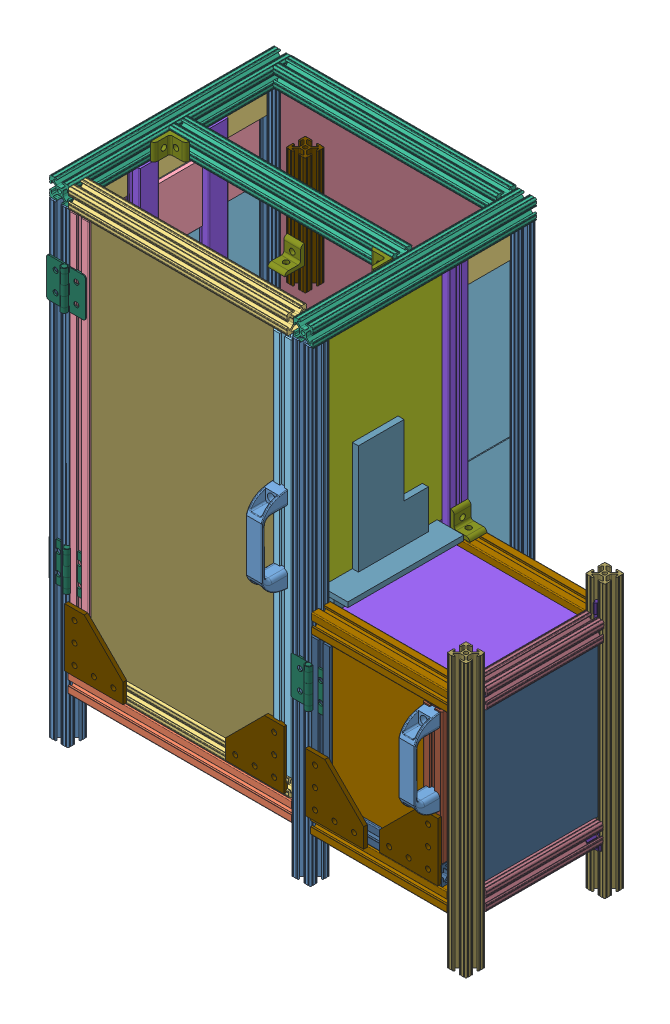
SolidWorks assembly Box_Miniscope_12.15.23, configuration Default. Lengths in mm.
Overall size (547.36 663.01 328.21).
94 component instances, 37 part files, 0 mates.
Components (placement in the parent):
- 24in47065T801_T-Slotted Framing-3: 24in47065T801_T-Slotted Framing [47065T801] at (-148.3949 609.6 -36.7617) x (1 0 0) z (0 -1 0) size (25.4 25.4 609.6)
- 24in47065T801_T-Slotted Framing-4: 24in47065T801_T-Slotted Framing [47065T801] at (168.7277 611.3932 -36.4525) x (1 0 0) z (0 -1 0) size (25.4 25.4 609.6)
- 11_5in6575N217_T-Slotted Framing Rail-4: 11_5in6575N217_T-Slotted Framing Rail [6575N217] at (10.5466 379.0665 -36.3692) x (0 0 -1) z (-1 0 0) size (25.4 25.4 292.1)
- 11_25in47065T846_T-Slotted Framing-3: 11_25in47065T846_T-Slotted Framing [47065T846] at (10.2279 404.6784 -36.3352) x (0 1 0) z (1 0 0) size (25.4 25.4 285.75)
- 11_25in47065T846_T-Slotted Framing-4: 11_25in47065T846_T-Slotted Framing [47065T846] at (7.8735 926.401 -36.5473) x (0 1 0) z (1 0 0) size (25.4 25.4 285.75)
- 19_5in6575N217_T-Slotted Framing Rail-2: 19_5in6575N217_T-Slotted Framing Rail [6575N217] at (-120.6393 666.1262 -36.1499) x (-1 0 0) z (0 1 0) size (25.4 25.4 495.3)
- 19_5in6575N218_T-Slotted Framing Rail-2: 19_5in6575N218_T-Slotted Framing Rail [6575N218] at (144.1698 664.3767 -36.7725) x (0 -1 0) z (0 0 -1) size (495.3 25.4 25.4)
- 24in47065T801_T-Slotted Framing-5: 24in47065T801_T-Slotted Framing [47065T801] at (168.71 609.2978 -305.5515) x (0 0 -1) z (0 1 0) size (25.4 25.4 609.6)
- 24in47065T801_T-Slotted Framing-6: 24in47065T801_T-Slotted Framing [47065T801] at (-148.3772 610.174 -305.8603) x (0 0 1) z (0 -1 0) size (25.4 25.4 609.6)
- 11_5in6575N217_T-Slotted Framing Rail-3: 11_5in6575N217_T-Slotted Framing Rail [6575N217] at (9.9362 357.1562 -305.5314) x (0 -1 0) z (1 0 0) size (25.4 25.4 292.1)
- 11_5in47065T801_T-Slotted Framing rail-5: 11_5in47065T801_T-Slotted Framing rail [47065T801] at (9.5197 928.5713 -305.435) x (0 1 0) z (-1 0 0) size (25.4 25.4 292.1)
- 9_5in6575N217_T-Slotted Framing Rail-1: 9_5in6575N217_T-Slotted Framing Rail [6575N217] at (167.4188 378.7448 -170.818) x (0 -1 0) z (0 0 1) size (25.4 25.4 241.3)
- 20_5in6575N217_T-Slotted Framing Rail-1: 20_5in6575N217_T-Slotted Framing Rail [6575N217] at (169.0181 653.0398 -217.2746) x (0 0 1) z (0 1 0) size (25.4 25.4 520.7)
- 9_5in6575N217_T-Slotted Framing Rail-2: 9_5in6575N217_T-Slotted Framing Rail [6575N217] at (-148.7212 378.985 -171.6941) size (25.4 25.4 241.3)
- 20_5in6575N217_T-Slotted Framing Rail-3: 20_5in6575N217_T-Slotted Framing Rail [6575N217] at (-147.9442 653.0983 -129.9903) x (0 0 -1) z (0 1 0) size (25.4 25.4 520.7)
- 11_5in47065T801_T-Slotted Framing rail-4: 11_5in47065T801_T-Slotted Framing rail [47065T801] at (-148.9741 926.7859 -172.2295) size (25.4 25.4 292.1)
- 11_5in47065T801_T-Slotted Framing rail-3: 11_5in47065T801_T-Slotted Framing rail [47065T801] at (169.5966 925.9079 -171.9377) size (25.4 25.4 292.1)
- 11_5in47065T801_T-Slotted Framing rail-6: 11_5in47065T801_T-Slotted Framing rail [47065T801] at (9.9058 928.9683 -169.0346) x (0 0 -1) z (1 0 0) size (25.4 25.4 292.1)
- 7in_6575N217_T-Slotted Framing Rail-1: 7in_6575N217_T-Slotted Framing Rail [6575N217] at (271.1061 378.8161 -35.8111) x (0 0 -1) z (-1 0 0) size (25.4 25.4 177.8)
- 7in_6575N217_T-Slotted Framing Rail-2: 7in_6575N217_T-Slotted Framing Rail [6575N217] at (271.3604 604.6105 -36.7818) x (0 0 1) z (-1 0 0) size (25.4 25.4 177.8)
- 6_75in6575N217_T-Slotted Framing Rail-1: 6_75in6575N217_T-Slotted Framing Rail [6575N217] at (194.7736 504.9941 -36.2462) x (-1 0 0) z (0 1 0) size (25.4 25.4 171.45)
- 6_75in6575N217_T-Slotted Framing Rail-2: 6_75in6575N217_T-Slotted Framing Rail [6575N217] at (267.6114 404.8421 -35.8111) x (0 0 1) z (-1 0 0) size (25.4 25.4 171.45)
- 6_75__6575N218_T-Slotted Framing Rail-1: 6_75__6575N218_T-Slotted Framing Rail [6575N218] at (340.4492 503.9229 -36.2462) x (0 -1 0) z (0 0 -1) size (171.45 25.4 25.4)
- 7in_6575N217_T-Slotted Framing Rail-4: 7in_6575N217_T-Slotted Framing Rail [6575N217] at (270.952 378.5991 -217.604) x (0 0 -1) z (-1 0 0) size (25.4 25.4 177.8)
- 7in_6575N217_T-Slotted Framing Rail-5: 7in_6575N217_T-Slotted Framing Rail [6575N217] at (270.952 604.0749 -217.5035) x (0 0 -1) z (1 0 0) size (25.4 25.4 177.8)
- 14_47065T801_T-Slotted Framing-1: 14_47065T801_T-Slotted Framing [47065T801] at (371.9906 482.5001 -36.2612) x (1 0 0) z (0 -1 0) size (25.4 25.4 355.6)
- 14_47065T801_T-Slotted Framing-2: 14_47065T801_T-Slotted Framing [47065T801] at (372.2567 481.9645 -217.2846) x (1 0 0) z (0 -1 0) size (25.4 25.4 355.6)
- 6in_47065T846_T-Slotted Framing-1: 6in_47065T846_T-Slotted Framing [47065T846] at (372.26 379.2027 -125.7835) x (0 -1 0) z (0 0 1) size (25.4 25.4 152.4)
- 6in_47065T846_T-Slotted Framing-2: 6in_47065T846_T-Slotted Framing [47065T846] at (372.2095 606.8098 -127.0918) x (0.999962 -0.008727 0) z (0 0 1) size (25.4 25.4 152.4)
- social_door-1: social_door [Default] at (146.7993 714.5703 -100.9995) x (0 0 -1) z (0 -1 0) size (151.57 54.86 424.8)
- 47065T347_T-Slotted Framing-1: 47065T347_T-Slotted Framing [47065T347] at (181.069 533.8996 -25.7652) size (50.8 51.89 8.3)
- 47065T236_Silver Corner Bracket-1: 47065T236_Silver Corner Bracket [47065T236] at (182.3045 618.2386 -216.7553) size (25.4 25.4 22.23)
- 5537T315_T-Slotted Framing-1: 5537T315_T-Slotted Framing [5537T315] at (372.0391 610.1548 -210.8032) x (0 0 -1) z (0 1 0) size (11.3 21 21)
- 5537T315_T-Slotted Framing-2: 5537T315_T-Slotted Framing [5537T315] at (362.8223 607.2352 -35.7039) x (0 0 1) z (-1 0 0) size (11.3 21 21)
- 47065T236_Silver Corner Bracket-2: 47065T236_Silver Corner Bracket [47065T236] at (181.3564 378.3142 -229.9872) x (1 0 0) z (0 1 0) size (25.4 25.4 22.23)
- 5537T315_T-Slotted Framing-3: 5537T315_T-Slotted Framing [5537T315] at (370.3719 377.8618 -38.5067) x (0 0 -1) z (-1 0 0) size (11.3 21 21)
- 5537T315_T-Slotted Framing-4: 5537T315_T-Slotted Framing [5537T315] at (377.537 378.1435 -216.1498) x (0 0 -1) z (-1 0 0) size (11.3 21 21)
- 5537T315_T-Slotted Framing-5: 5537T315_T-Slotted Framing [5537T315] at (169.9879 383.5329 -40.7588) x (0 0 -1) z (0 -1 0) size (11.3 21 21)
- 5537T315_T-Slotted Framing-6: 5537T315_T-Slotted Framing [5537T315] at (168.2275 604.5945 -41.9909) x (0 0 -1) z (1 0 0) size (11.3 21 21)
- 5537T315_T-Slotted Framing-7: 5537T315_T-Slotted Framing [5537T315] at (170.6355 381.8637 -39.2531) x (-1 0 0) z (0 -0.999962 0.008727) size (11.3 21 21)
- 5537T315_T-Slotted Framing-8: 5537T315_T-Slotted Framing [5537T315] at (368.2177 604.5945 -216.2178) size (11.3 21 21)
- 5537T315_T-Slotted Framing-9: 5537T315_T-Slotted Framing [5537T315] at (373.0966 601.9539 -41.1786) x (-1 0 0) z (0 0 -1) size (11.3 21 21)
- 5537T315_T-Slotted Framing-10: 5537T315_T-Slotted Framing [5537T315] at (364.0014 371.2097 -38.5379) x (1 0 0) z (0 0 -1) size (11.3 21 21)
- 5537T315_T-Slotted Framing-11: 5537T315_T-Slotted Framing [5537T315] at (374.683 376.4911 -207.4156) x (-1 0 0) z (0 0 1) size (11.3 21 21)
- 47065T267_T-Slotted Framing-1: 47065T267_T-Slotted Framing [47065T267] at (181.3084 390.387 -19.4749) size (76.2 76.2 4.76)
- 47065T267_T-Slotted Framing-2: 47065T267_T-Slotted Framing [47065T267] at (352.5726 395.6684 -21.1893) x (0 1 0) z (0 0 1) size (76.2 76.2 4.76)
- 47065T595_Red Plastic Pull Handle-1: 47065T595_Red Plastic Pull Handle [47065T595] at (339.9991 485.6035 -26.6998) size (21.11 112.11 36)
- 47065T595_Red Plastic Pull Handle-2: 47065T595_Red Plastic Pull Handle [47065T595] at (140.8802 637.8823 -26.3458) size (21.11 112.11 36)
- 47065T347_T-Slotted Framing-2: 47065T347_T-Slotted Framing [47065T347] at (-135.5102 507.7072 -26.6883) size (50.8 51.89 8.3)
- 47065T347_T-Slotted Framing-3: 47065T347_T-Slotted Framing [47065T347] at (-136.3904 826.3483 -24.2642) size (50.8 51.89 8.3)
- 47065T267_T-Slotted Framing-3: 47065T267_T-Slotted Framing [47065T267] at (-132.3149 397.4288 -18.8727) size (76.2 76.2 4.76)
- 47065T267_T-Slotted Framing-4: 47065T267_T-Slotted Framing [47065T267] at (149.8575 397.4288 -22.9011) x (0 1 0) z (0 0 1) size (76.2 76.2 4.76)
- lever-2: lever [Default] at (-150.1673 475.0434 -228.178) x (0 0 -1) z (0 -1 0) size (77.83 17.27 82.55)
- lever-3: lever [Default] at (-152.8537 475.9236 -46.8874) x (0 0 -1) z (0 -1 0) size (77.83 17.27 82.55)
- 20_5in6575N217_T-Slotted Framing Rail-4: 20_5in6575N217_T-Slotted Framing Rail [6575N217] at (-149.6364 651.4107 -222.2621) x (0 0 -1) z (0 1 0) size (25.4 25.4 520.7)
- pC-1: pC [Default] at (-151.3902 874.9313 -225.4723) x (0 0 -1) z (0 1 0) size (76.2 4.76 38.1)
- pC-2: pC [Default] at (-151.3902 874.022 -134.5396) x (0 0 -1) z (0 1 0) size (76.2 4.76 38.1)
- pC-3: pC [Default] at (-151.3902 874.9313 -43.607) x (0 0 -1) z (0 1 0) size (76.2 4.76 38.1)
- pB-1: pB [Default] at (-154.7481 799.5031 -300.763) x (0 1 0) z (0 0 1) size (76.2 4.76 76.2)
- pB-2: pB [Default] at (-145.65 797.6844 -213.4676) x (0 1 0) z (0 0 1) size (76.2 4.76 76.2)
- pB-3: pB [Default] at (-153.056 798.5937 -121.6256) x (0 1 0) z (0 0 1) size (76.2 4.76 76.2)
- pA-1: pA [Default] at (-154.7481 596.8761 -299.8537) x (0 1 0) z (0 0 1) size (203.2 4.76 76.2)
- small_Panel_houselight-3: small_Panel_houselight [Default] at (-155.5233 594.5358 -224.073) x (0 0 -1) z (0 -1 0) size (81.28 32 41.27)
- small_Panel_houselight-4: small_Panel_houselight [Default] at (-155.8368 593.6265 -41.9384) x (0 0 -1) z (0 -1 0) size (81.28 32 41.27)
- pA-5: pA [Default] at (-147.1666 592.6741 -207.5193) x (0 1 0) z (0 0 1) size (203.2 4.76 76.2)
- pA-6: pA [Default] at (-148.9828 594.1481 -116.7497) x (0 1 0) z (0 0 1) size (203.2 4.76 76.2)
- pA-7: pA [Default] at (-151.3289 390.27 -210.457) x (0 1 0) z (0 0 1) size (203.2 4.76 76.2)
- pB-7: pB [Default] at (-143.1716 475.7828 -300.7902) x (0 1 0) z (0 0 1) size (76.2 4.76 76.2)
- pB-9: pB [Default] at (-151.3289 474.8735 -117.7031) x (0 1 0) z (0 0 1) size (76.2 4.76 76.2)
- pA-8: pA [Default] at (170.6671 470.4797 -302.5816) x (0 1 0) z (0 0 1) size (203.2 4.76 76.2)
- pA-9: pA [Default] at (169.9555 674.1689 -300.763) x (0 1 0) z (0 0 1) size (203.2 4.76 76.2)
- pC-4: pC [Default] at (173.3134 876.7424 -230.0189) x (0 0 -1) z (0 1 0) size (76.2 4.76 38.1)
- pD-1: pD [Default] at (166.9824 621.9972 -213.3606) x (0 1 0) z (0 0 1) size (298.45 4.76 165.1)
- pG-1: pG [Default] at (187.7197 602.9271 -209.473) size (171.45 4.76 165.1)
- pF-1: pF [Default] at (198.2205 411.574 -31.1345) x (0 1 0) z (1 0 0) size (180.97 4.76 136.53)
- pH-1: pH [Default] at (374.4689 391.1371 -208.814) x (0 1 0) z (0 0 1) size (200.03 4.76 165.1)
- pE-1: pE [Default] at (181.2356 391.3683 -219.3294) x (0 1 0) z (1 0 0) size (203.2 4.76 190.5)
- pJ-1: pJ [Default] at (130.9188 414.9153 -26.2757) x (0 1 0) z (-1 0 0) size (501.65 4.76 250.83)
- pI-1: pI [Default] at (-145.0751 370.6353 -313.66) x (0 1 0) z (1 0 0) size (542.92 4.76 304.8)
- pK-1: pK [Default] at (232.8933 383.0615 -43.7679) x (0 0 -1) z (-1 0 0) size (165.1 4.76 50.8)
- pK-2: pK [Default] at (290.9789 383.0615 -45.5831) x (0 0 -1) z (-1 0 0) size (165.1 4.76 50.8)
- pL-1: pL [Default] at (300.0735 378.299 -45.5831) x (0 0 -1) z (1 0 0) size (165.1 4.76 25.4)
- pL-2: pL [Default] at (333.3517 378.299 -44.373) x (0 0 -1) z (1 0 0) size (165.1 4.76 25.4)
- pN-1: pN [Default] at (-134.9574 369.6788 -296.8821) size (50.8 4.76 254)
- pN-2: pN [Default] at (-76.2667 369.6788 -297.4872) size (50.8 4.76 254)
- pN-3: pN [Default] at (-17.576 369.6788 -297.4872) size (50.8 4.76 254)
- pN-4: pN [Default] at (41.1146 369.5616 -300.5125) size (50.8 4.76 254)
- pM-1: pM [Default] at (99.7435 369.8757 -298.0922) size (23.09 4.76 254)
- pM-2: pM [Default] at (130.6015 370.07 -298.6973) size (23.09 4.76 254)
- 6in_47065T801_T-Slotted Framing-1: 6in_47065T801_T-Slotted Framing [47065T801] at (2.1886 890.9714 -196.2041) x (1 0 0) z (0 -1 0) size (25.4 25.4 152.4)
- 47065T236_Silver Corner Bracket-3: 47065T236_Silver Corner Bracket [47065T236] at (3.0893 845.8313 -183.0471) x (-0.008727 0 0.999962) z (-0.999962 0 -0.008727) size (25.4 25.4 22.23)
- 47065T236_Silver Corner Bracket-8: 47065T236_Silver Corner Bracket [47065T236] at (-134.3586 927.2107 -155.9595) x (1 0 0) z (0 -1 0) size (25.4 25.4 22.23)
- 47065T236_Silver Corner Bracket-9: 47065T236_Silver Corner Bracket [47065T236] at (156.0571 927.6019 -156.5646) x (0 0 1) z (0 -1 0) size (25.4 25.4 22.23)
- food_port_R001-1: food_port_R001 [Default] at (169.6136 400.2241 -261.8177) x (0 0 1) z (-1 0 0) size (76.2 76.2 85.19)
